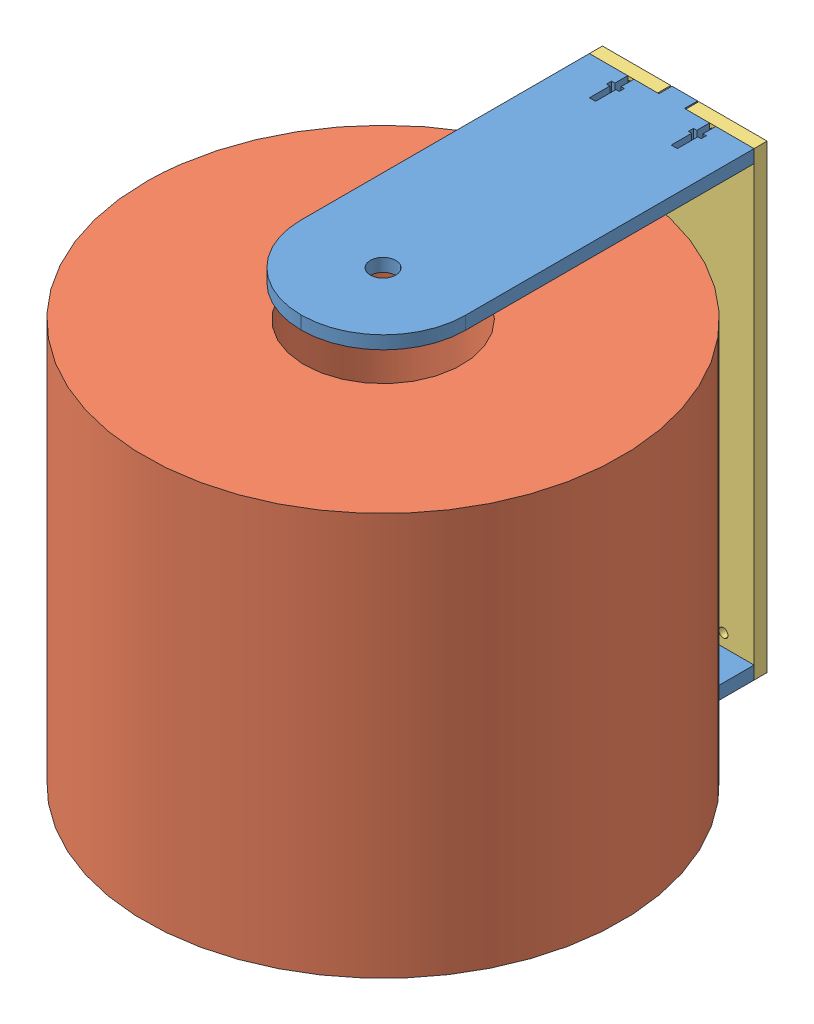
SolidWorks assembly assem, configuration Default. Lengths in mm.
Overall size (253.46 228.6 276.59).
4 component instances, 3 part files, 9 mates.
Components (placement in the parent):
- support-1: support [Default] at (-38.9877 231.671 195.7702) x (0 0 1) z (0 -1 0) size (190.5 81.79 6.48)
- tp-1: tp [Default] at (-38.9877 431.569 250.3802) x (-0.997119 0 -0.075857) z (0 -1 0) size (236.22 236.22 199.9)
- singlemount-1: singlemount [Default] at (-38.9877 339.494 100.5202) size (81.79 228.6 6.48)
- support-3: support [Default] at (-38.9877 447.317 195.7702) x (0 0 1) z (0 1 0) size (190.5 81.79 6.48)
Mates (geometry in assembly coordinates):
- Parallel1: parallel anti-aligned: plane of support-1 through (-38.9877 231.671 195.7702) normal (0 1 0); plane of tp-1 through (-38.9877 231.671 250.3802) normal (0 -1 0)
- Concentric1: concentric aligned: cylinder of support-1 through (-38.9877 225.194 250.3802) axis (0 1 0) radius 6.35; cylinder of tp-1 through (-38.9877 231.671 250.3802) axis (0 1 0) radius 39.116
- Coincident7: coincident anti-aligned: plane of support-1 through (-38.9877 231.671 195.7702) normal (0 1 0); plane of tp-1 through (-38.9877 231.671 250.3802) normal (0 -1 0)
- Coincident8: coincident anti-aligned: plane of support-1 through (-38.9877 225.194 106.9972) normal (0 0 -1); plane of singlemount-1 through (-38.9877 339.494 106.9972) normal (0 0 1)
- Distance2: distance = 0.635 mm anti-aligned: plane of support-1 through (-45.3377 225.194 195.7702) normal (-1 0 0); plane of singlemount-1 through (-45.9727 339.494 106.9972) normal (1 0 0)
- Coincident10: coincident anti-aligned: plane of support-1 through (-38.9877 231.671 195.7702) normal (0 1 0); plane of singlemount-1 through (-38.9877 231.671 106.9972) normal (0 -1 0)
- Distance3: distance = 0.635 mm anti-aligned: plane of support-3 through (-45.3377 453.794 195.7702) normal (-1 0 0); plane of singlemount-1 through (-45.9727 339.494 106.9972) normal (1 0 0)
- Coincident14: coincident anti-aligned: plane of singlemount-1 through (-38.9877 339.494 106.9972) normal (0 0 1); plane of support-3 through (-38.9877 453.794 106.9972) normal (0 0 -1)
- Coincident15: coincident anti-aligned: plane of singlemount-1 through (-38.9877 447.317 106.9972) normal (0 1 0); plane of support-3 through (-38.9877 447.317 195.7702) normal (0 -1 0)
